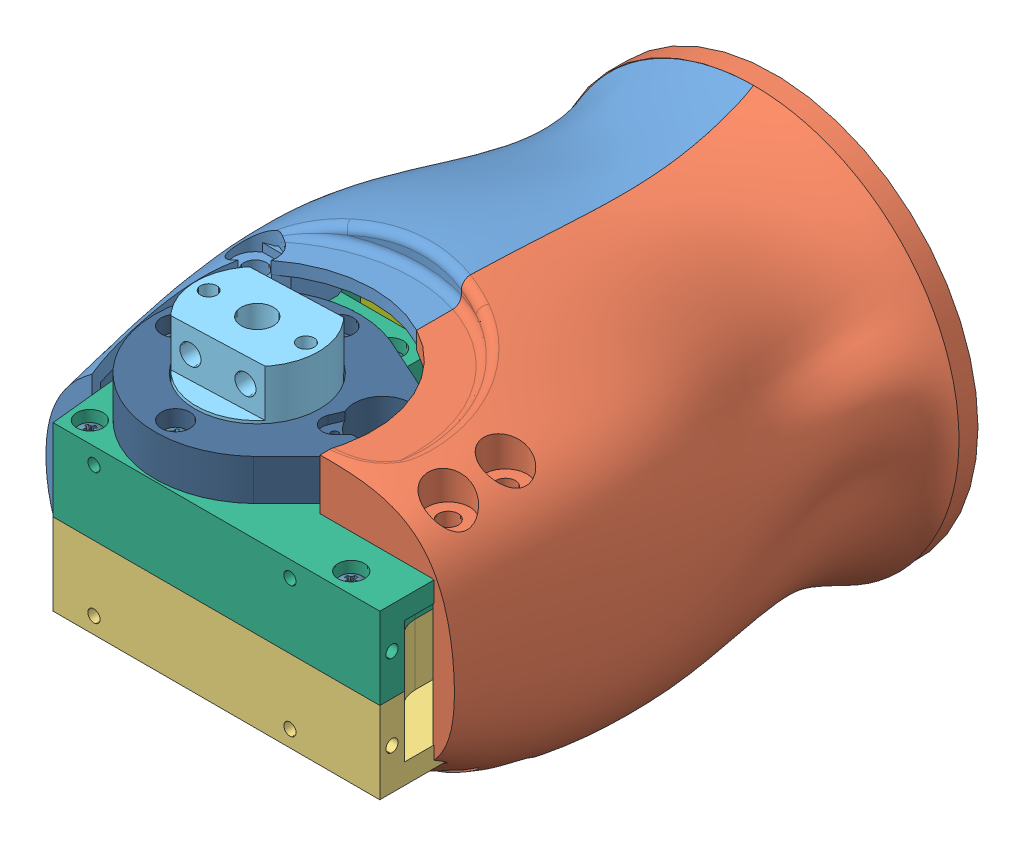
SolidWorks assembly lower arm assm, configuration Default. Lengths in mm.
Overall size (109.85 109.64 138.38).
31 component instances, 14 part files, 4 mates.
Components (placement in the parent):
- arm lower bottom-1: arm lower bottom [Default] at (-82.8839 14.8285 33.6624) size (59.85 109.64 120.63)
- arm lower top-1: arm lower top [Default] at (-82.8839 14.8285 33.6624) size (102.83 109.64 125.02)
- gearbox-1: gearbox [Default] at (-90.004 25.8046 38.1582) size (88.25 74 125.51)
  - bottom housing-1: bottom housing [Default] at (7.4002 -24.2748 89.7718) x (1 0 0) z (0 1 0) size (87.5 78 20)
  - wormscrew-1: wormscrew [Default] at (21.4002 -4.2748 74.7718) x (-0.98645 0.164063 0) z (0 0 1) size (40 40 51)
  - driveshaft cog-1: driveshaft cog [Default] at (-6.5998 -9.2748 103.2718) x (-0.999334 0 0.036493) z (0 1 0) size (49.29 49.31 47)
  - top housing-1: top housing [Default] at (-6.5998 15.7252 103.2718) x (-1 0 0) z (0 -1 0) size (87.5 78 40)
  - HS-805BB-1: HS-805BB [Default] at (2.9002 10.7252 28.6693) x (1 0 0) z (0 -1 0) size (83 68.8 30)
  - 608ZZ-4: 608ZZ [Default] at (21.4002 -4.2748 120.5718) x (0.996867 0.079098 0) z (0 0 1) size (22 22 7)
  - 6806 30x42x7-1: 6806 30x42x7 [Default] at (-6.5998 -15.2748 103.2718) x (0.979879 0 0.199591) z (0 -1 0) size (42 42 7)
  - 6806 30x42x7-2: 6806 30x42x7 [Default] at (-6.5998 2.7252 103.2718) x (0.968275 0 0.249889) z (0 1 0) size (42 42 7)
  - pot holder-1: pot holder [Default] at (-6.5998 15.7252 103.2718) x (0 0 -1) z (0 1 0) size (50 60 10)
  - cog brace-1: cog brace [Default] at (18.6002 10.0252 104.6718) x (-1 0 0) z (0 -1 0) size (8.5 22.65 3)
  - pot cog-1: pot cog [Default] at (18.6002 10.0252 97.7718) x (0.754384 0 -0.656434) z (0 1 0) size (28 27.88 7.9)
  - driveshaft-1: driveshaft [Default] at (-6.5998 -9.2748 103.2718) x (0.999334 0 -0.036493) z (0 -1 0) size (36.44 35.48 27)
  - Pan Head Cross Recess Screw_ISO-22: Pan Head Cross Recess Screw_ISO [ISO 7045 - M3 x 10 - Z --- 10N] at (-26.5998 23.1252 103.2718) x (0 -1 0) z (0 0 1) size (12.35 5.6 5.6)
  - Pan Head Cross Recess Screw_ISO-23: Pan Head Cross Recess Screw_ISO [ISO 7045 - M3 x 10 - Z --- 10N] at (-6.5998 23.1252 123.2718) x (0 -1 0) z (0.495758 0 0.868461) size (12.35 5.6 5.6)
  - Pan Head Cross Recess Screw_ISO-24: Pan Head Cross Recess Screw_ISO [ISO 7045 - M3 x 10 - Z --- 10N] at (-6.5998 23.1252 83.2718) x (0 -1 0) z (0.927545 0 0.373711) size (12.35 5.6 5.6)
  - Pan Head Cross Recess Screw_ISO-3: Pan Head Cross Recess Screw_ISO [ISO 7045 - M5 x 12 - Z --- 12N] at (-34.5998 -13.2748 42.0718) x (0 0 1) z (-1 0 0) size (15.63 9.5 9.5)
  - Pan Head Cross Recess Screw_ISO-4: Pan Head Cross Recess Screw_ISO [ISO 7045 - M5 x 12 - Z --- 12N] at (-34.5998 4.7252 42.0718) x (0 0 1) z (-1 0 0) size (15.63 9.5 9.5)
  - Pan Head Cross Recess Screw_ISO-9: Pan Head Cross Recess Screw_ISO [ISO 7045 - M3 x 30 - Z --- 25N] at (36.9002 14.1252 123.7718) x (0 -1 0) z (0 0 1) size (32.35 5.6 5.6)
  - Pan Head Cross Recess Screw_ISO-13: Pan Head Cross Recess Screw_ISO [ISO 7045 - M3 x 30 - Z --- 25N] at (-18.0998 -22.6748 69.7718) x (0 1 0) z (0 0 1) size (32.35 5.6 5.6)
  - Pan Head Cross Recess Screw_ISO-14: Pan Head Cross Recess Screw_ISO [ISO 7045 - M3 x 30 - Z --- 25N] at (34.9002 14.1252 82.7718) x (0 -1 0) z (-0.981395 0 -0.191999) size (32.35 5.6 5.6)
  - Pan Head Cross Recess Screw_ISO-15: Pan Head Cross Recess Screw_ISO [ISO 7045 - M3 x 30 - Z --- 25N] at (-5.5998 14.1252 71.7718) x (0 -1 0) z (0.38373 0 0.923445) size (32.35 5.6 5.6)
  - Pan Head Cross Recess Screw_ISO-16: Pan Head Cross Recess Screw_ISO [ISO 7045 - M2 x 6 - Z --- 6N] at (18.6002 6.9252 115.2718) x (0 1 0) z (0.879308 0 -0.476254) size (7.57 4 4)
  - Pan Head Cross Recess Screw_ISO-18: Pan Head Cross Recess Screw_ISO [ISO 7045 - M3 x 5 - Z --- 5N] at (-5.9795 -13.6748 120.2605) x (0 1 0) z (-0.276322 0 0.961065) size (7.35 5.6 5.6)
  - Pan Head Cross Recess Screw_ISO-19: Pan Head Cross Recess Screw_ISO [ISO 7045 - M3 x 5 - Z --- 5N] at (7.8026 -13.6748 94.2402) x (0 1 0) z (0 0 1) size (7.35 5.6 5.6)
  - Pan Head Cross Recess Screw_ISO-20: Pan Head Cross Recess Screw_ISO [ISO 7045 - M3 x 5 - Z --- 5N] at (-21.6227 -13.6748 95.3147) x (0 1 0) z (-0.051559 0 0.99867) size (7.35 5.6 5.6)
  - Pan Head Cross Recess Screw_ISO-21: Pan Head Cross Recess Screw_ISO [ISO 7045 - M3 x 30 - Z --- 25N] at (-27.0895 14.1252 123.7718) x (0 -1 0) z (-0.304842 0 0.952403) size (32.35 5.6 5.6)
  - Pan Head Cross Recess Screw_ISO-2: Pan Head Cross Recess Screw_ISO [ISO 7045 - M5 x 12 - Z --- 12N] at (40.4002 4.7252 42.0718) x (0 0 1) z (0.747712 -0.664023 0) size (15.63 9.5 9.5)
  - Pan Head Cross Recess Screw_ISO-1: Pan Head Cross Recess Screw_ISO [ISO 7045 - M5 x 12 - Z --- 12N] at (40.4002 -13.2748 42.0718) x (0 0 1) z (0.337086 -0.941474 0) size (15.63 9.5 9.5)
Mates (geometry in assembly coordinates):
- Concentric1: concentric anti-aligned: cylinder of ?; cylinder of gearbox-1/top housing-1
- Concentric2: concentric anti-aligned: cylinder of ?; cylinder of gearbox-1/top housing-1
- Coincident1: coincident aligned: plane of ? through (-82.5637 24.5544 33.6624) normal (0 0 -1); plane of ? through (-82.5637 24.5544 33.6624) normal (0 0 -1)
- Coincident3: coincident: point of ?; point of gearbox-1/top housing-1
